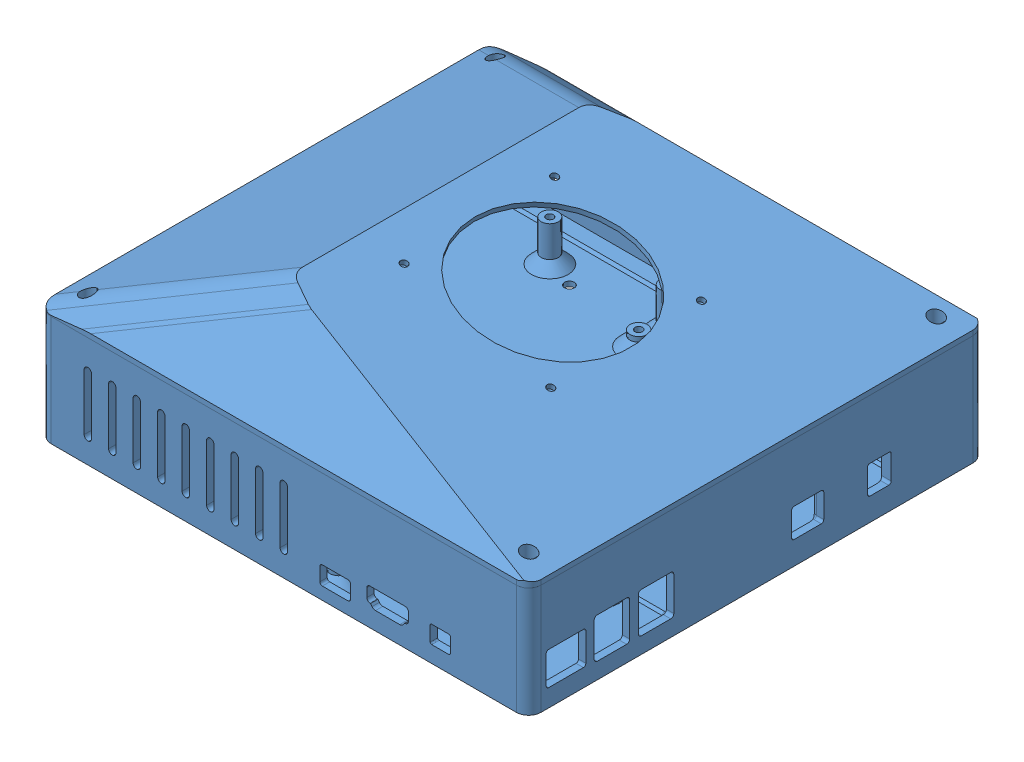
SolidWorks assembly Electronics_support, configuration Default. Lengths in mm.
Overall size (200 34 186.38).
7 component instances, 7 part files, 13 mates.
Components (placement in the parent):
- Electronics_support-1: Electronics_support [Default] at origin size (200 77 186.38)
- Crawler_PCB-1: Crawler_PCB [Default] at (47.0462 15.67 24.8894) x (-0.999987 0 0.005076) z (0 1 0) size (176.15 95.16 1.6) (hidden)
- RaspberryPi 3-1: RaspberryPi 3 [Detailed] at (15.6444 3 94.4681) x (1 0 0) z (0 1 0) size (87.05 58.5 19.05) (hidden)
- Arduino Mega 2560-2: Arduino Mega 2560 [Default] at (1.9694 5 -0.3319) size (109.91 15.26 53.6) (hidden)
- GPS_NEO-6M-1: GPS_NEO-6M [Default] at (-65.3556 10 115.4681) x (0 0 1) z (-1 0 0) size (24.5 4.3 40.75) (hidden)
- 70x70x25_Fan-1: 70x70x25_Fan [Default] at (-26.7281 37.0654 34.2764) x (-0.974064 0.226274 0) z (0.226274 0.974064 0) size (76.67 76.67 16.27) (hidden)
- Fan_cover-1: Fan_cover [Default] at origin size (70.59 18.24 72) (hidden)
Mates (geometry in assembly coordinates):
- Distance4: distance = 3 mm anti-aligned: plane of RaspberryPi 3-1 through (15.6444 3 94.4681) normal (0 -1 0)
- Coincident15: coincident aligned: plane of Crawler_PCB-1 through (47.0462 15.67 -0.3319) normal (0 0 1)
- Parallel2: parallel aligned: plane of Crawler_PCB-1 through (-32.9547 17.27 30.6812) normal (0 0 1); plane of Arduino Mega 2560-2 through (-45.2556 6.63 26.4681) normal (0 0 1)
- Coincident23: coincident anti-aligned: plane of Electronics_support-1 through (0 5 0) normal (0 1 0); plane of Arduino Mega 2560-2 through (1.9694 5 -0.3319) normal (0 -1 0)
- Parallel4: parallel anti-aligned: plane of Electronics_support-1 through (-130.2556 35 120.4681) normal (0 0 -1); plane of GPS_NEO-6M-1 through (-82.3556 11.3 115.4681) normal (0 0 1)
- Distance11: distance = 10 mm anti-aligned: plane of GPS_NEO-6M-1 through (-64.1056 10 103.2181) normal (0 -1 0); plane of Electronics_support-1 through (0 0 0) normal (0 1 0)
- Concentric8: concentric aligned: cylinder of Electronics_support-1 through (-79.3556 10 93.9681) axis (0 -1 0) radius 1.5; cylinder of GPS_NEO-6M-1 through (-79.3556 11.3 93.9681) axis (0 -1 0) radius 2
- Parallel6: parallel aligned: plane of Electronics_support-1 through (62.7444 44 -261.1527) normal (0.226274 0.974064 0); plane of 70x70x25_Fan-1 through (-21.0712 61.417 34.2764) normal (0.226274 0.974064 0)
- Concentric10: concentric aligned: cylinder of Electronics_support-1 through (-27.1806 35.1173 34.2764) axis (0.226274 0.974064 0) radius 32.5; cylinder of 70x70x25_Fan-1 through (-26.7281 37.0654 34.2764) axis (0.226274 0.974064 0) radius 33.4
- Concentric12: concentric aligned: cylinder of Electronics_support-1 through (-57.1331 42.0752 65.0264) axis (0.226274 0.974064 0) radius 1.5; cylinder of 70x70x25_Fan-1 through (-51.0237 68.3749 65.0264) axis (0.226274 0.974064 0) radius 2.2128
- Coincident31: coincident aligned: circle of Electronics_support-1; plane of 70x70x25_Fan-1 through (-21.0712 61.417 34.2764) normal (0.226274 0.974064 0)
- Distance12: distance = 40 mm anti-aligned: plane of RaspberryPi 3-1 through (-26.8556 4.3 66.4681) normal (0 0 -1); plane of Arduino Mega 2560-2 through (-45.2556 6.63 26.4681) normal (0 0 1)
- Coincident33: coincident aligned: plane of Crawler_PCB-1 through (47.0462 15.67 -0.3319) normal (0 0 1); plane of Arduino Mega 2560-2 through (1.9694 5 -0.3319) normal (0 0 1)
